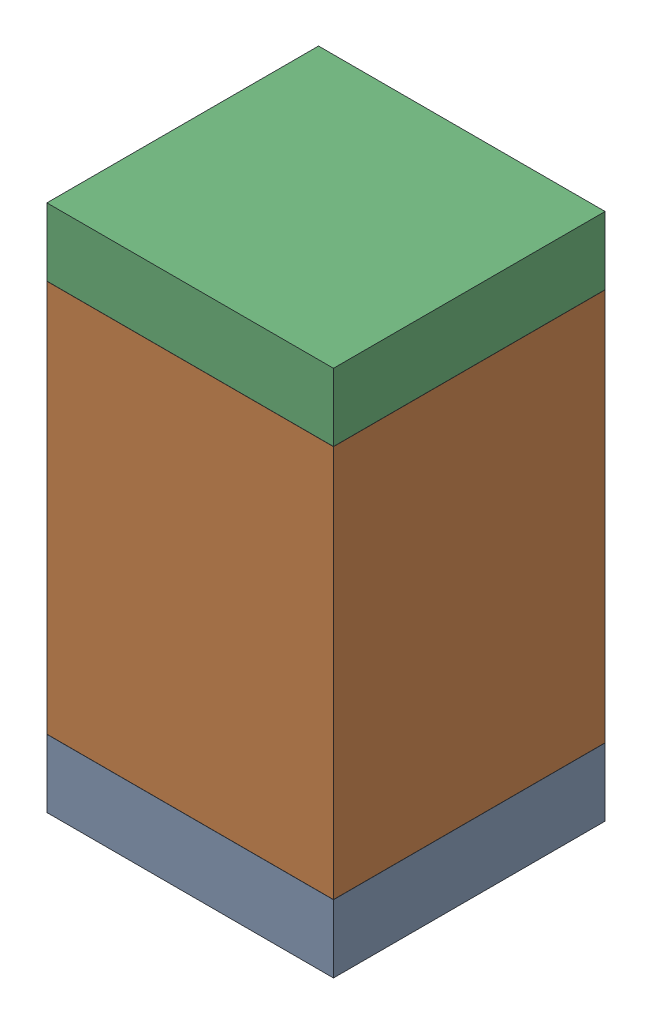
SolidWorks assembly C21, configuration Default. Lengths in mm.
Overall size (1.9 3.5 1.8).
6 component instances, 2 part files, 0 mates.
Components (placement in the parent):
- 6638397408-1: 6638397408 [Default] at (25.5269 9.1431 0) size (1.9 0.45 1.8)
  - Extruded_16-1: Extruded_16 [Default] at origin size (1.9 0.45 1.8)
- 6638397248-1: 6638397248 [Default] at (25.5269 10.6681 0) size (1.9 2.6 1.8)
  - Extruded_17-1: Extruded_17 [Default] at origin size (1.9 2.6 1.8)
- 6638397408-2: 6638397408 [Default] at (25.5269 12.1931 0) size (1.9 0.45 1.8)
  - Extruded_16-1: Extruded_16 [Default] at origin size (1.9 0.45 1.8)
